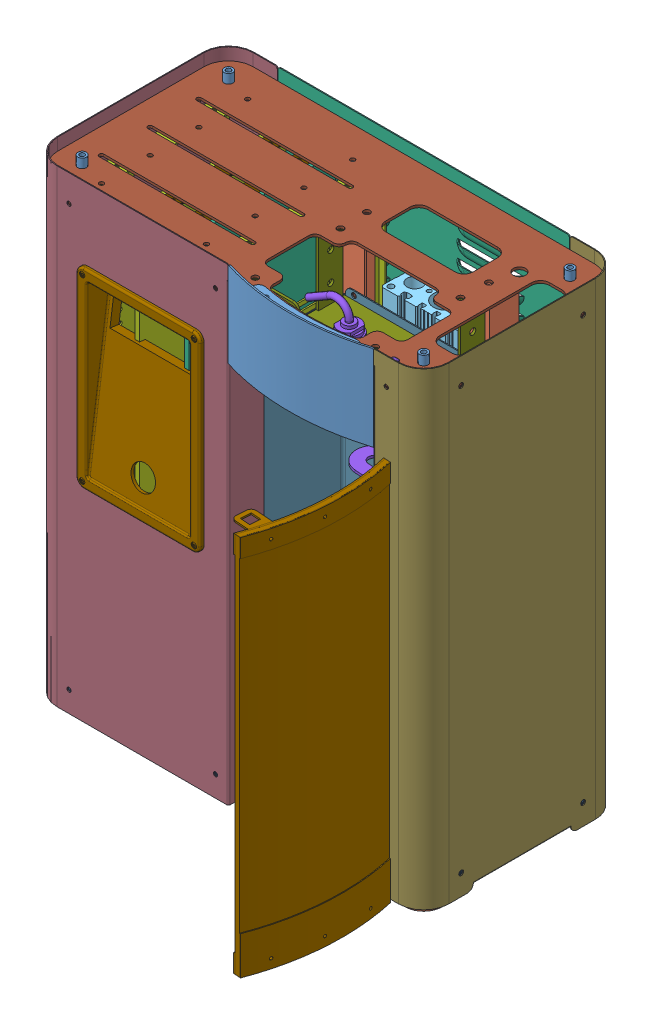
SolidWorks assembly PBS_000_ASSEM, configuration Default. Lengths in mm.
Overall size (408.18 494.12 354.89).
43 component instances, 30 part files, 76 mates.
Components (placement in the parent):
- PBS_251_P_SHELL_TOP PANEL_SPCR-1: PBS_251_P_SHELL_TOP PANEL_SPCR [Default] at (-177.8 466.09 -25.4) size (8.89 9.53 8.89)
- PBS_251_P_SHELL_TOP PANEL_SPCR-2: PBS_251_P_SHELL_TOP PANEL_SPCR [Default] at (177.8 466.09 -177.8) size (8.89 9.53 8.89)
- PBS_251_P_SHELL_TOP PANEL_SPCR-3: PBS_251_P_SHELL_TOP PANEL_SPCR [Default] at (-177.8 466.09 -177.8) size (8.89 9.53 8.89)
- PBS_251_P_SHELL_TOP PANEL_SPCR-4: PBS_251_P_SHELL_TOP PANEL_SPCR [Default] at (177.8 466.09 -25.4) x (-0.950356 0 -0.311163) z (0.311163 0 -0.950356) size (8.89 9.53 8.89)
- PBS_260_P_SHELL_FEET-1: PBS_260_P_SHELL_FEET [Default] at (-177.8 -15.24 -25.4) x (0.99233 0 -0.123619) z (-0.123619 0 -0.99233) size (38.1 12.7 38.1)
- PBS_260_P_SHELL_FEET-2: PBS_260_P_SHELL_FEET [Default] at (-177.8 -15.24 -177.8) x (0.99233 0 -0.123619) z (-0.123619 0 -0.99233) size (38.1 12.7 38.1)
- PBS_260_P_SHELL_FEET-3: PBS_260_P_SHELL_FEET [Default] at (177.8 -15.24 -177.8) x (0.99233 0 -0.123619) z (-0.123619 0 -0.99233) size (38.1 12.7 38.1)
- PBS_260_P_SHELL_FEET-4: PBS_260_P_SHELL_FEET [Default] at (177.8 -15.24 -25.4) x (0.99233 0 -0.123619) z (-0.123619 0 -0.99233) size (38.1 12.7 38.1)
- PBS_351_X_SLIDER_CYLNDR_RODS-2: PBS_351_X_SLIDER_CYLNDR_RODS [Default] at (0 3.5007 0) size (16 184.53 16)
- PBS_352_X_SLIDER_CYLNDR_PLATE-2: PBS_352_X_SLIDER_CYLNDR_PLATE [Default] at (0 3.5007 0) size (91.44 10.16 38.1)
- PBS_250_P_SHELL_TOP PANEL-2: PBS_250_P_SHELL_TOP PANEL [Default] at origin size (406.4 3.17 214.14) (hidden)
- PBS_350_X_SLIDER_CYLNDR_BODY-2: PBS_350_X_SLIDER_CYLNDR_BODY [Default] at origin size (93 213.36 42)
- PBS_351_X_SLIDER_CYLNDR_RODS-3: PBS_351_X_SLIDER_CYLNDR_RODS [Default] at (64 3.5007 0) size (16 184.53 16)
- PBS_660-1: PBS_660 [Default] at (-63.8173 0 -18.0046) x (0 0 -1) z (1 0 0) size (152.4 463.55 4.76)
- PBS_710-1: PBS_710 [Default] at (-110.7002 0 -170.4046) x (0 0 1) z (-1 0 0) size (152.4 463.55 4.76)
- PBS_400-1: PBS_400 [Default] at (76.2 347.8213 -49.4386) size (69.38 110.78 50.8)
- PBS_410_P_CNTRLPNL-1: PBS_410_P_CNTRLPNL [Default] at (0.0048 0.0048 0) size (167.85 220.8 39.34)
- PBS_110_S_CHASSIS_PLATE_B-2: PBS_110_S_CHASSIS_PLATE_B [Default] at origin size (406.51 28.11 203.31)
- PBS_120_S_CHASSIS_PLATE_T-1: PBS_120_S_CHASSIS_PLATE_T [Default] at origin size (406.51 28 214.19)
- PBS_210_S_SHELL_R_a-1: PBS_210_S_SHELL_R_a [Default] at origin size (64.39 487.68 204.98)
- PBS_220_S_SHELL_L-1: PBS_220_S_SHELL_L [Default] at origin size (214.26 487.68 205.36)
- PBS_230_S_SHELL_BACKSPLASH-1: PBS_230_S_SHELL_BACKSPLASH [Default] at origin size (177.8 429.08 94.88)
- PBS_310_S_SLIDER_PLATFRM-1: PBS_310_S_SLIDER_PLATFRM [Default] at (0.236 3.5007 0) size (146.05 28.04 118.2)
- PBS_150_S_CHASSIS_FILLHD PLATE_a-1: PBS_150_S_CHASSIS_FILLHD PLATE_a [Default] at (0 3.175 0) size (156.98 80.48 128.96)
- PBS_151_S_CHASSIS_FILLHD PLATE_PLUG-1: PBS_151_S_CHASSIS_FILLHD PLATE_PLUG [Default] at (0 3.175 0) size (57.65 7.64 59.13)
- PBS_610-1: PBS_610 [Default] at (-42.5236 0 0) size (15.97 16.98 129.7)
- PBS_225_S_SHELL_VALENCE-2: PBS_225_S_SHELL_VALENCE [Default] at origin size (151.65 88.99 22.27)
- PBS_130_S_CHASSIS_POST_L-R-2: PBS_130_S_CHASSIS_POST_L-R [Default] at (-1.905 0 0) size (22.22 463.55 30.79)
- PBS_330_S_SLIDER_CYLNDR_BRKT-2: PBS_330_S_SLIDER_CYLNDR_BRKT [Default] at origin size (147.66 258.26 27.55)
- PBS_320_S_SLIDER_PLATFRM_BRKT-2: PBS_320_S_SLIDER_PLATFRM_BRKT [Default] at (0 3.5007 0) size (101.6 28.96 165.1)
- PBS_130_S_CHASSIS_POST_L-R-3: PBS_130_S_CHASSIS_POST_L-R [Default] at (154.305 463.55 0) x (-1 0 0) z (0 0 1) size (22.22 463.55 30.79)
- PBS_610-2: PBS_610 [Default] at (-131.9939 0 -188.2463) x (-1 0 0) z (0 0 -1) size (15.97 16.98 129.7)
- PBS_610-3: PBS_610 [Default] at (-42.5236 463.55 -188.2463) x (1 0 0) z (0 0 -1) size (15.97 16.98 129.7)
- PBS_610-4: PBS_610 [Default] at (-131.9939 463.55 0) x (-1 0 0) z (0 0 1) size (15.97 16.98 129.7)
- PBS_140_S_CHASSIS_BULKHEAD-1: PBS_140_S_CHASSIS_BULKHEAD [Default] at (9.525 0 -203.2) x (-1 0 0) z (0 -1 0) size (158.75 28 63.5)
- PBS_240_S_SHELL_BACK PANEL-1: PBS_240_S_SHELL_BACK PANEL [Default] at (0 237.49 -203.2) x (-1 0 0) z (0 0 -1) size (303.53 482.6 9.52)
- PBS-171_S_CHASSIS_CMPNT BRD_R-1: PBS-171_S_CHASSIS_CMPNT BRD_R [Default] at (-13.134 0 -171.1369) x (0 0 1) z (-1 0 0) size (152.4 463.55 26.92)
- PBS-171_S_CHASSIS_CMPNT BRD_R-2: PBS-171_S_CHASSIS_CMPNT BRD_R [Default] at (-171.6049 0 -18.7369) x (0 0 -1) z (1 0 0) size (152.4 463.55 26.92)
- Assem1^PBS_000_ASSEM-1: Assem1^PBS_000_ASSEM [Default] at (162.052 231.775 -9.525) x (-0.069437 0 0.997586) z (-0.997586 0 -0.069437) size (167.04 477.52 47.55) (virtual)
  - Axle Concept-1: Axle Concept [Default] at origin size (39.75 473.71 34.25)
  - Door Concept-1: Door Concept [Default] at (85.87 -240.665 -5.345) x (-1 0 0) z (0 0 -1) size (146.34 397 34.5)
- PBS_650_X_DOOR_DAMPER_a-1: PBS_650_X_DOOR_DAMPER_a [Default] at (169.8382 389.89 -16.1074) x (-1 0 0) z (0 0 1) size (15 7.2 24)
- PBS_654_X_DOOR_SWITCH-1: PBS_654_X_DOOR_SWITCH [Default] at (183.7941 353.4815 -20.0471) x (1 0 0) z (0 -1 0) size (28.57 6.35 44.56)
Mates (geometry in assembly coordinates):
- Coincident56: coincident anti-aligned: plane of PBS_110_S_CHASSIS_PLATE_B-2 through (0 0 0) normal (0 1 0); plane of PBS_610-1 through (-42.5236 0 0) normal (0 -1 0)
- Coincident58: coincident anti-aligned: plane of PBS_120_S_CHASSIS_PLATE_T-1 through (127 463.55 10.1854) normal (0 -1 0); plane of PBS_130_S_CHASSIS_POST_L-R-3 through (154.305 463.55 0) normal (0 1 0)
- Coincident59: coincident anti-aligned: plane of PBS_230_S_SHELL_BACKSPLASH-1 through (1.905 616.2986 -119.126) normal (0 0 -1); plane of PBS_130_S_CHASSIS_POST_L-R-3 through (152.4 -35.2099 -119.126) normal (0 0 1)
- Coincident65: coincident aligned: plane of PBS_320_S_SLIDER_PLATFRM_BRKT-2 through (0 3.5007 0) normal (0 0 1); plane of assembly through (0 0 0) normal (0 0 1)
- Distance2: distance = 5.08 mm anti-aligned: plane of PBS_320_S_SLIDER_PLATFRM_BRKT-2 through (0 5.08 0) normal (0 -1 0); plane of PBS_110_S_CHASSIS_PLATE_B-2 through (0 0 0) normal (0 1 0)
- Coincident67: coincident aligned: plane of PBS_310_S_SLIDER_PLATFRM-1 through (0.236 3.5007 0) normal (0 0 1); plane of assembly through (0 0 0) normal (0 0 1)
- Coincident70: coincident anti-aligned: plane of PBS_310_S_SLIDER_PLATFRM-1 through (25.636 28.9007 -88.9) normal (0 -1 0); plane of PBS_320_S_SLIDER_PLATFRM_BRKT-2 through (152.872 28.9007 0) normal (0 1 0)
- Coincident71: coincident anti-aligned: plane of PBS_110_S_CHASSIS_PLATE_B-2 through (0 0 0) normal (0 1 0); plane of PBS_610-2 through (-131.9939 0 -188.2463) normal (0 -1 0)
- Parallel2: parallel aligned: plane of PBS_110_S_CHASSIS_PLATE_B-2 through (-176.6349 491.49 -143.4345) normal (0 0 -1); plane of PBS_610-2 through (-94.8252 1.016 -158.9746) normal (0 0 -1)
- Coincident73: coincident aligned: plane of PBS_610-1 through (-79.6923 1.016 -158.9746) normal (0 0 -1); plane of PBS_610-2 through (-94.8252 1.016 -158.9746) normal (0 0 -1)
- Parallel3: parallel anti-aligned: plane of PBS_610-1 through (-64.8333 16.891 -29.2717) normal (-1 0 0); plane of PBS_610-2 through (-109.6842 16.891 -158.9746) normal (1 0 0)
- Coincident75: coincident anti-aligned: plane of PBS_120_S_CHASSIS_PLATE_T-1 through (127 463.55 10.1854) normal (0 -1 0); plane of PBS_610-4 through (-131.9939 463.55 0) normal (0 1 0)
- Coincident76: coincident aligned: plane of PBS_610-2 through (-110.7002 1.016 -158.9746) normal (-1 0 0); plane of PBS_610-4 through (-110.7002 462.534 -29.2717) normal (-1 0 0)
- Coincident77: coincident aligned: plane of PBS_610-2 through (-94.8252 1.016 -158.9746) normal (0 0 -1); plane of PBS_610-4 through (-94.8252 462.534 -158.9746) normal (0 0 -1)
- Coincident78: coincident anti-aligned: plane of PBS_120_S_CHASSIS_PLATE_T-1 through (127 463.55 10.1854) normal (0 -1 0); plane of PBS_610-3 through (-42.5236 463.55 -188.2463) normal (0 1 0)
- Coincident79: coincident aligned: plane of PBS_610-1 through (-63.8173 1.016 -29.2717) normal (1 0 0); plane of PBS_610-3 through (-63.8173 462.534 -158.9746) normal (1 0 0)
- Coincident80: coincident aligned: plane of PBS_610-1 through (-79.6923 1.016 -158.9746) normal (0 0 -1); plane of PBS_610-3 through (-79.6923 462.534 -158.9746) normal (0 0 -1)
- Concentric54: concentric anti-aligned: cylinder of PBS_120_S_CHASSIS_PLATE_T-1 through (177.8 453.39 -177.8) axis (0 1 0) radius 2.7051; cylinder of PBS_251_P_SHELL_TOP PANEL_SPCR-2 through (177.8 475.615 -177.8) axis (0 -1 0) radius 4.445
- Concentric55: concentric anti-aligned: cylinder of PBS_120_S_CHASSIS_PLATE_T-1 through (-177.8 453.39 -177.8) axis (0 1 0) radius 2.7051; cylinder of PBS_251_P_SHELL_TOP PANEL_SPCR-3 through (-177.8 475.615 -177.8) axis (0 -1 0) radius 4.445
- Concentric57: concentric anti-aligned: cylinder of PBS_120_S_CHASSIS_PLATE_T-1 through (177.8 453.39 -25.4) axis (0 1 0) radius 2.7051; cylinder of PBS_251_P_SHELL_TOP PANEL_SPCR-4 through (177.8 475.615 -25.4) axis (0 -1 0) radius 4.445
- Coincident87: coincident anti-aligned: plane of PBS_120_S_CHASSIS_PLATE_T-1 through (-177.8 466.09 -25.4) normal (0 1 0); plane of PBS_251_P_SHELL_TOP PANEL_SPCR-3 through (-177.8 466.09 -177.8) normal (0 -1 0)
- Coincident88: coincident anti-aligned: plane of PBS_120_S_CHASSIS_PLATE_T-1 through (-177.8 466.09 -25.4) normal (0 1 0); plane of PBS_251_P_SHELL_TOP PANEL_SPCR-1 through (-177.8 466.09 -25.4) normal (0 -1 0)
- Coincident89: coincident anti-aligned: plane of PBS_120_S_CHASSIS_PLATE_T-1 through (-177.8 466.09 -25.4) normal (0 1 0); plane of PBS_251_P_SHELL_TOP PANEL_SPCR-4 through (177.8 466.09 -25.4) normal (0 -1 0)
- Coincident90: coincident anti-aligned: plane of PBS_120_S_CHASSIS_PLATE_T-1 through (-177.8 466.09 -25.4) normal (0 1 0); plane of PBS_251_P_SHELL_TOP PANEL_SPCR-2 through (177.8 466.09 -177.8) normal (0 -1 0)
- Coincident91: coincident anti-aligned: plane of PBS_110_S_CHASSIS_PLATE_B-2 through (0 -2.54 0) normal (0 -1 0); plane of PBS_260_P_SHELL_FEET-1 through (-177.8 -2.54 -25.4) normal (0 1 0)
- Coincident93: coincident anti-aligned: plane of PBS_110_S_CHASSIS_PLATE_B-2 through (0 -2.54 0) normal (0 -1 0); plane of PBS_260_P_SHELL_FEET-3 through (177.8 -2.54 -177.8) normal (0 1 0)
- Coincident94: coincident anti-aligned: plane of PBS_110_S_CHASSIS_PLATE_B-2 through (0 -2.54 0) normal (0 -1 0); plane of PBS_260_P_SHELL_FEET-4 through (177.8 -2.54 -25.4) normal (0 1 0)
- Coincident95: coincident anti-aligned: plane of PBS_110_S_CHASSIS_PLATE_B-2 through (0 -2.54 0) normal (0 -1 0); plane of PBS_260_P_SHELL_FEET-2 through (-177.8 -2.54 -177.8) normal (0 1 0)
- Coincident96: coincident anti-aligned: plane of PBS_320_S_SLIDER_PLATFRM_BRKT-2 through (0 8.1997 0) normal (0 1 0); plane of PBS_352_X_SLIDER_CYLNDR_PLATE-2 through (0 8.1997 0) normal (0 -1 0)
- Coincident97: coincident aligned: plane of PBS_352_X_SLIDER_CYLNDR_PLATE-2 through (0 3.5007 0) normal (1 0 0); plane of assembly through (0 0 0) normal (1 0 0)
- Coincident98: coincident aligned: plane of PBS_352_X_SLIDER_CYLNDR_PLATE-2 through (0 3.5007 0) normal (0 0 1); plane of assembly through (0 0 0) normal (0 0 1)
- Coincident99: coincident anti-aligned: plane of PBS_351_X_SLIDER_CYLNDR_RODS-2 through (44.2 18.3597 -149.651) normal (0 -1 0); plane of PBS_352_X_SLIDER_CYLNDR_PLATE-2 through (0 18.3597 0) normal (0 1 0)
- Coincident100: coincident anti-aligned: plane of PBS_352_X_SLIDER_CYLNDR_PLATE-2 through (0 18.3597 0) normal (0 1 0); plane of PBS_351_X_SLIDER_CYLNDR_RODS-3 through (108.2 18.3597 -149.651) normal (0 -1 0)
- Concentric63: concentric anti-aligned: cylinder of PBS_351_X_SLIDER_CYLNDR_RODS-2 through (44.2 225.5182 -149.651) axis (0 -1 0) radius 8; cylinder of PBS_350_X_SLIDER_CYLNDR_BODY-2 through (44.2 195.7324 -149.651) axis (0 1 0) radius 8
- Concentric64: concentric anti-aligned: cylinder of PBS_350_X_SLIDER_CYLNDR_BODY-2 through (108.2 195.7324 -149.651) axis (0 1 0) radius 8; cylinder of PBS_351_X_SLIDER_CYLNDR_RODS-3 through (108.2 225.5182 -149.651) axis (0 -1 0) radius 8
- Concentric65: concentric anti-aligned: cylinder of PBS_120_S_CHASSIS_PLATE_T-1 through (-177.8 453.39 -25.4) axis (0 1 0) radius 2.7051; cylinder of PBS_251_P_SHELL_TOP PANEL_SPCR-1 through (-177.8 475.615 -25.4) axis (0 -1 0) radius 4.445
- Coincident105: coincident aligned: plane of PBS_610-1 through (-42.5236 0 0) normal (0 0 1); plane of assembly through (0 0 0) normal (0 0 1)
- Coincident106: coincident aligned: plane of PBS_610-4 through (-131.9939 463.55 0) normal (0 0 1); plane of assembly through (0 0 0) normal (0 0 1)
- Coincident110: coincident anti-aligned: plane of PBS_120_S_CHASSIS_PLATE_T-1 through (127 463.55 10.1854) normal (0 -1 0); plane of PBS_660-1 through (-59.0548 463.55 -18.0046) normal (0 1 0)
- Coincident111: coincident anti-aligned: plane of PBS_610-3 through (-63.8173 462.534 -158.9746) normal (1 0 0); plane of PBS_660-1 through (-63.8173 0 -18.0046) normal (-1 0 0)
- Coincident112: coincident anti-aligned: plane of PBS_120_S_CHASSIS_PLATE_T-1 through (127 463.55 10.1854) normal (0 -1 0); plane of PBS_710-1 through (-115.4627 463.55 -170.4046) normal (0 1 0)
- Coincident113: coincident anti-aligned: plane of PBS_610-4 through (-110.7002 462.534 -29.2717) normal (-1 0 0); plane of PBS_710-1 through (-110.7002 0 -170.4046) normal (1 0 0)
- Coincident114: coincident anti-aligned: plane of PBS_110_S_CHASSIS_PLATE_B-2 through (0 0 0) normal (0 1 0); plane of PBS_140_S_CHASSIS_BULKHEAD-1 through (-149.225 0 -200.66) normal (0 -1 0)
- Coincident115: coincident aligned: plane of PBS_110_S_CHASSIS_PLATE_B-2 through (-203.2 -2.54 -203.2) normal (0 0 -1); plane of PBS_140_S_CHASSIS_BULKHEAD-1 through (9.525 0 -203.2) normal (0 0 -1)
- Coincident117: coincident anti-aligned: plane of PBS_120_S_CHASSIS_PLATE_T-1 through (177.8 466.09 -203.2) normal (0 0 -1); plane of PBS_240_S_SHELL_BACK PANEL-1 through (0 237.49 -203.2) normal (0 0 1)
- Coincident118: coincident anti-aligned: plane of PBS_240_S_SHELL_BACK PANEL-1 through (0 237.49 -203.2) normal (-1 0 0); plane of assembly through (0 0 0) normal (1 0 0)
- Coincident119: coincident aligned: plane of PBS_210_S_SHELL_R_a-1 through (177.8 478.79 -177.8) normal (0 1 0); plane of PBS_240_S_SHELL_BACK PANEL-1 through (151.765 478.79 -204.216) normal (0 1 0)
- Coincident120: coincident anti-aligned: plane of PBS_120_S_CHASSIS_PLATE_T-1 through (127 463.55 10.1854) normal (0 -1 0); plane of PBS-171_S_CHASSIS_CMPNT BRD_R-1 through (-14.658 463.55 -171.1369) normal (0 1 0)
- Parallel4: parallel anti-aligned: plane of PBS_230_S_SHELL_BACKSPLASH-1 through (0 -4.699 -118.11) normal (-1 0 0); plane of PBS-171_S_CHASSIS_CMPNT BRD_R-1 through (-13.134 0 -171.1369) normal (1 0 0)
- Concentric66: concentric anti-aligned: cylinder of PBS_150_S_CHASSIS_FILLHD PLATE_a-1 through (76.2 348.869 -49.4386) axis (0 1 0) radius 6.7469; cylinder of PBS_400-1 through (76.2 347.8213 -49.4386) axis (0 -1 0) radius 6.35
- Coincident122: coincident anti-aligned: plane of PBS_150_S_CHASSIS_FILLHD PLATE_a-1 through (76.2 393.065 -242.3006) normal (0 1 0); plane of PBS_400-1 through (82.55 393.065 -49.4386) normal (0 -1 0)
- Coincident123: coincident anti-aligned: plane of PBS_110_S_CHASSIS_PLATE_B-2 through (0 0 0) normal (0 1 0); plane of PBS-171_S_CHASSIS_CMPNT BRD_R-2 through (-170.0809 0 -18.7369) normal (0 -1 0)
- Coincident124: coincident aligned: plane of PBS-171_S_CHASSIS_CMPNT BRD_R-1 through (-14.658 0 -171.1369) normal (0 0 -1); plane of PBS-171_S_CHASSIS_CMPNT BRD_R-2 through (-170.0809 0 -171.1369) normal (0 0 -1)
- Coincident125: coincident anti-aligned: circle of PBS_110_S_CHASSIS_PLATE_B-2; cylinder of PBS_260_P_SHELL_FEET-1 through (-177.8 2.54 -25.4) axis (0 -1 0) radius 3.175
- Concentric67: concentric anti-aligned: circle of PBS_110_S_CHASSIS_PLATE_B-2; cylinder of PBS_260_P_SHELL_FEET-4 through (177.8 -2.54 -25.4) axis (0 -1 0) radius 19.05
- Distance4: distance = 11.43 mm aligned: plane of PBS_660-1 through (-59.0548 463.55 -170.4046) normal (0 0 -1); plane of PBS_610-1 through (-79.6923 1.016 -158.9746) normal (0 0 -1)
- Coincident129: coincident aligned: plane of PBS_660-1 through (-59.0548 463.55 -170.4046) normal (0 0 -1); plane of PBS_710-1 through (-115.4627 0 -170.4046) normal (0 0 -1)
- Distance5: distance = 1.905 mm aligned: plane of assembly through (0 0 0) normal (1 0 0); plane of PBS_130_S_CHASSIS_POST_L-R-2 through (-1.905 0 0) normal (1 0 0)
- Distance6: distance = 154.305 mm anti-aligned: plane of PBS_130_S_CHASSIS_POST_L-R-3; plane of assembly through (0 0 0) normal (1 0 0)
- Coincident134: coincident anti-aligned: plane of PBS_120_S_CHASSIS_PLATE_T-1 through (127 463.55 10.1854) normal (0 -1 0); plane of PBS_150_S_CHASSIS_FILLHD PLATE_a-1 through (0 463.55 0) normal (0 1 0)
- Coincident135: coincident aligned: plane of PBS_150_S_CHASSIS_FILLHD PLATE_a-1 through (0 3.175 0) normal (1 0 0); plane of assembly through (0 0 0) normal (1 0 0)
- Coincident136: coincident anti-aligned: plane of PBS_310_S_SLIDER_PLATFRM-1 through (25.636 5.0247 -114.0149) normal (1 0 0); plane of PBS_320_S_SLIDER_PLATFRM_BRKT-2 through (25.636 5.0247 -168.619) normal (-1 0 0)
- Coincident137: coincident anti-aligned: plane of PBS_220_S_SHELL_L-1 through (0 761.6947 0.889) normal (0 0 1); plane of PBS_410_P_CNTRLPNL-1 through (0.0048 0.0048 0.889) normal (0 0 -1)
- Coincident138: coincident anti-aligned: plane of PBS_150_S_CHASSIS_FILLHD PLATE_a-1 through (76.2 393.065 -242.3006) normal (0 1 0); plane of PBS_151_S_CHASSIS_FILLHD PLATE_PLUG-1 through (46.6442 393.065 -54.6413) normal (0 -1 0)
- Concentric71: concentric aligned: cylinder of PBS_120_S_CHASSIS_PLATE_T-1 through (13.716 461.01 -102.87) axis (0 1 0) radius 3.302; cylinder of PBS_150_S_CHASSIS_FILLHD PLATE_a-1 through (13.716 438.15 -102.87) axis (0 1 0) radius 4.064
- Concentric72: concentric aligned: cylinder of PBS_150_S_CHASSIS_FILLHD PLATE_a-1 through (76.2 348.869 -49.4386) axis (0 1 0) radius 6.7469; cylinder of PBS_151_S_CHASSIS_FILLHD PLATE_PLUG-1 through (76.2 332.1491 -49.4386) axis (0 1 0) radius 6.7469
- Parallel5: parallel aligned: plane of PBS_151_S_CHASSIS_FILLHD PLATE_PLUG-1 through (82.8469 332.1491 8.5607) normal (1 0 0); plane of assembly through (0 0 0) normal (1 0 0)
- Distance8: distance = 6.35 mm anti-aligned: plane of PBS_110_S_CHASSIS_PLATE_B-2 through (-155.575 0 -200.66) normal (1 0 0); plane of PBS_140_S_CHASSIS_BULKHEAD-1 through (-149.225 25.4 -200.66) normal (-1 0 0)
- Concentric76: concentric aligned: cylinder of PBS_120_S_CHASSIS_PLATE_T-1 through (162.052 468.63 -9.525) axis (0 -1 0) radius 1.7145; cylinder of Assem1^PBS_000_ASSEM-1/Axle Concept-1 through (162.052 468.63 -9.525) axis (0 -1 0) radius 2.3813
- Coincident145: coincident anti-aligned: plane of PBS_120_S_CHASSIS_PLATE_T-1 through (-177.8 466.09 -25.4) normal (0 1 0); plane of Assem1^PBS_000_ASSEM-1/Axle Concept-1 through (162.052 466.09 -9.525) normal (0 -1 0)
- Coincident146: coincident aligned: plane of PBS_220_S_SHELL_L-1 through (-177.8 -8.89 -177.8) normal (0 -1 0); plane of Assem1^PBS_000_ASSEM-1/Door Concept-1 through (-75.5773 -8.89 60.0126) normal (0 -1 0)
- Coincident147: coincident aligned: plane of PBS_320_S_SLIDER_PLATFRM_BRKT-2 through (0 3.5007 0) normal (1 0 0); plane of assembly through (0 0 0) normal (1 0 0)
- Coincident148: coincident anti-aligned: plane of PBS_210_S_SHELL_R_a-1 through (177.8 389.89 -25.4) normal (0 -1 0); plane of PBS_650_X_DOOR_DAMPER_a-1 through (169.8382 389.89 -16.1074) normal (0 1 0)
- Parallel11: parallel aligned: plane of PBS_210_S_SHELL_R_a-1 through (154.051 391.541 -33.2583) normal (0 0 -1); plane of PBS_650_X_DOOR_DAMPER_a-1 through (173.3382 387.39 -28.1074) normal (0 0 -1)
- Coincident150: coincident anti-aligned: plane of PBS_210_S_SHELL_R_a-1 through (0 0 -13.6971) normal (0 0 -1); plane of PBS_654_X_DOOR_SWITCH-1 through (183.7941 353.4815 -13.6971) normal (0 0 1)
- Parallel12: parallel aligned: plane of PBS_210_S_SHELL_R_a-1 through (196.1375 388.239 -27.9211) normal (1 0 0); plane of PBS_654_X_DOOR_SWITCH-1 through (194.9066 337.6065 -13.6971) normal (1 0 0)
